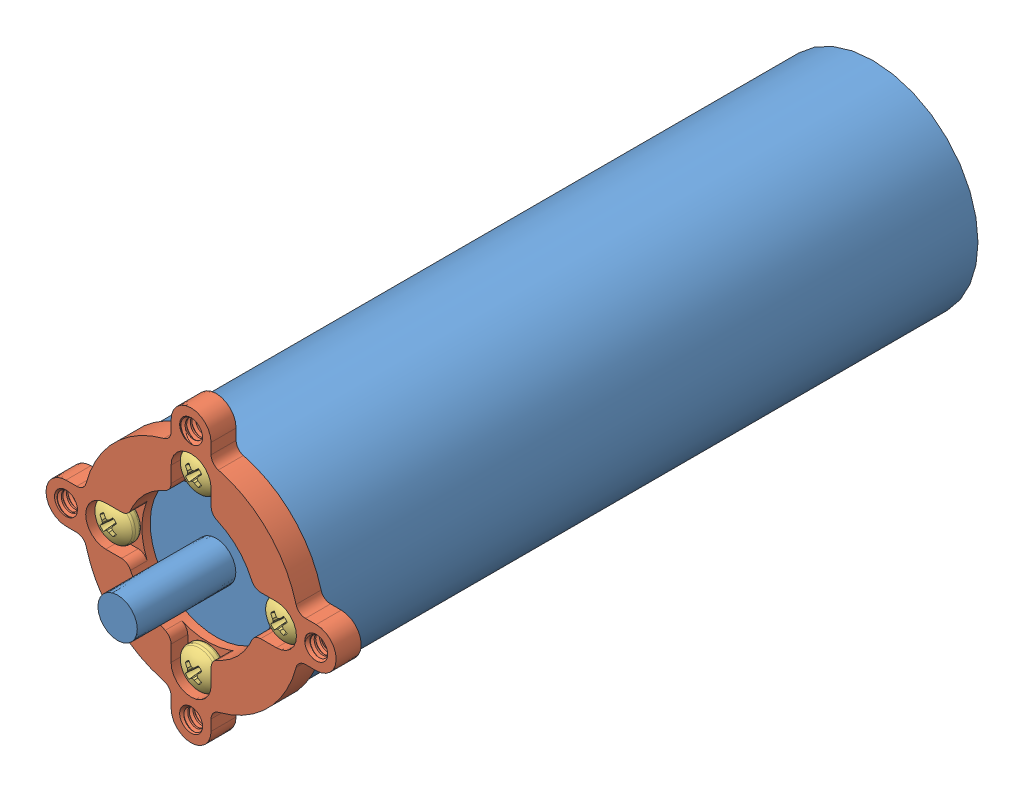
SolidWorks assembly Assem2, configuration Default. Lengths in mm.
Overall size (46.7 46.7 115).
7 component instances, 3 part files, 3 mates.
Components (placement in the parent):
- Motors-1: Motors [Default] at (81.834 51.8135 -31.3435) size (32 32 115)
- Motor_mount-2: Motor_mount [Default] at (45.268 5.1287 35.3702) x (-0.707107 -0.707107 0) z (-0.707107 0.707107 0) size (33.02 8.74 33.02)
  - 555174-1: 555174 [Default] at (-58.8675 33.2863 7.1552) size (33.02 4.05 33.02)
  - 555174 screw_92005A116-1: 555174 screw_92005A116 [Default] at (-68.0596 28.5563 -2.0369) x (1 0 0) z (0 1 0) size (6 6 8.48)
  - 555174 screw_92005A116-2: 555174 screw_92005A116 [Default] at (-68.0596 28.5563 16.3474) x (0 0 -1) z (0 1 0) size (6 6 8.48)
  - 555174 screw_92005A116-3: 555174 screw_92005A116 [Default] at (-49.6753 28.5563 16.3474) x (-1 0 0) z (0 1 0) size (6 6 8.48)
  - 555174 screw_92005A116-4: 555174 screw_92005A116 [Default] at (-49.6753 28.5563 -2.0369) x (0 0 1) z (0 1 0) size (6 6 8.48)
Mates (geometry in assembly coordinates):
- Concentric1: concentric: circle of Motors-1; cone of Motor_mount-2/555174 screw_92005A116-2 through (81.8343 64.8132 115.3899) axis (0 0 -1)
- Concentric4: concentric: circle of Motors-1; circle of Motor_mount-2/555174 screw_92005A116-1
- Coincident4: coincident anti-aligned: plane of Motors-1 through (81.834 51.8135 68.6565) normal (0 0 1); plane of Motor_mount-2/555174-1 through (81.834 51.8138 68.6565) normal (0 0 -1)
